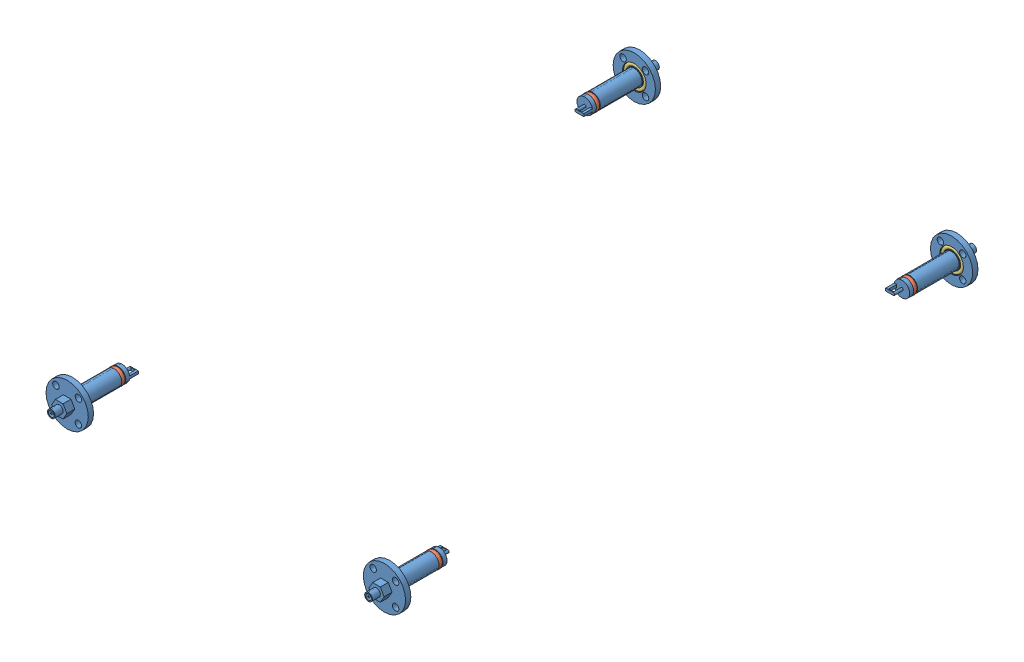
SolidWorks assembly sense_loop_quad_assy_a_1107, configuration Default. Lengths in mm.
Overall size (272 32 457).
32 component instances, 4 part files, 6 mates.
Components (placement in the parent):
- sense_loop_assy_a_1107-1: sense_loop_assy_a_1107 [Default] at (-120 0 -212.5) x (-1 0 0) z (0 0 1) size (32 32 60)
  - sense_loop_a_1107-1: sense_loop_a_1107 [Default] at origin size (32 32 60)
  - sense_loop_canted_1107-1: sense_loop_canted_1107 [Default] at (0 0 33) x (1 0 0) z (0 1 0) size (12 3 12)
  - sense_loop_oring_1107-1: sense_loop_oring_1107 [Default] at (0 0 -0.75) x (1 0 0) z (0 1 0) size (17.5 1.5 17.5)
  - Socket Head Cap Screw_AM-1: Socket Head Cap Screw_AM [B18.3.1M - 4 x 0.7 x 10 Hex SHCS -- 10NHX] at (-8.4853 -8.4853 -8) x (0 0 1) z (-0.030517 0.999534 0) size (14 7 7)
  - Socket Head Cap Screw_AM-2: Socket Head Cap Screw_AM [B18.3.1M - 4 x 0.7 x 10 Hex SHCS -- 10NHX] at (-8.4853 8.4853 -8) x (0 0 1) z (0.999534 0.030517 0) size (14 7 7)
  - Socket Head Cap Screw_AM-3: Socket Head Cap Screw_AM [B18.3.1M - 4 x 0.7 x 10 Hex SHCS -- 10NHX] at (8.4853 8.4853 -8) x (0 0 1) z (0.030517 -0.999534 0) size (14 7 7)
  - Socket Head Cap Screw_AM-4: Socket Head Cap Screw_AM [B18.3.1M - 4 x 0.7 x 10 Hex SHCS -- 10NHX] at (8.4853 -8.4853 -8) x (0 0 1) z (-0.999534 -0.030517 0) size (14 7 7)
- sense_loop_assy_a_1107-2: sense_loop_assy_a_1107 [Default] at (120 0 -212.5) size (32 32 60)
  - sense_loop_a_1107-1: sense_loop_a_1107 [Default] at origin size (32 32 60)
  - sense_loop_canted_1107-1: sense_loop_canted_1107 [Default] at (0 0 33) x (1 0 0) z (0 1 0) size (12 3 12)
  - sense_loop_oring_1107-1: sense_loop_oring_1107 [Default] at (0 0 -0.75) x (1 0 0) z (0 1 0) size (17.5 1.5 17.5)
  - Socket Head Cap Screw_AM-1: Socket Head Cap Screw_AM [B18.3.1M - 4 x 0.7 x 10 Hex SHCS -- 10NHX] at (-8.4853 -8.4853 -8) x (0 0 1) z (-0.030517 0.999534 0) size (14 7 7)
  - Socket Head Cap Screw_AM-2: Socket Head Cap Screw_AM [B18.3.1M - 4 x 0.7 x 10 Hex SHCS -- 10NHX] at (-8.4853 8.4853 -8) x (0 0 1) z (0.999534 0.030517 0) size (14 7 7)
  - Socket Head Cap Screw_AM-3: Socket Head Cap Screw_AM [B18.3.1M - 4 x 0.7 x 10 Hex SHCS -- 10NHX] at (8.4853 8.4853 -8) x (0 0 1) z (0.030517 -0.999534 0) size (14 7 7)
  - Socket Head Cap Screw_AM-4: Socket Head Cap Screw_AM [B18.3.1M - 4 x 0.7 x 10 Hex SHCS -- 10NHX] at (8.4853 -8.4853 -8) x (0 0 1) z (-0.999534 -0.030517 0) size (14 7 7)
- sense_loop_assy_a_1107-3: sense_loop_assy_a_1107 [Default] at (120 0 212.5) x (1 0 0) z (0 0 -1) size (32 32 60)
  - sense_loop_a_1107-1: sense_loop_a_1107 [Default] at origin size (32 32 60)
  - sense_loop_canted_1107-1: sense_loop_canted_1107 [Default] at (0 0 33) x (1 0 0) z (0 1 0) size (12 3 12)
  - sense_loop_oring_1107-1: sense_loop_oring_1107 [Default] at (0 0 -0.75) x (1 0 0) z (0 1 0) size (17.5 1.5 17.5)
  - Socket Head Cap Screw_AM-1: Socket Head Cap Screw_AM [B18.3.1M - 4 x 0.7 x 10 Hex SHCS -- 10NHX] at (-8.4853 -8.4853 -8) x (0 0 1) z (-0.030517 0.999534 0) size (14 7 7)
  - Socket Head Cap Screw_AM-2: Socket Head Cap Screw_AM [B18.3.1M - 4 x 0.7 x 10 Hex SHCS -- 10NHX] at (-8.4853 8.4853 -8) x (0 0 1) z (0.999534 0.030517 0) size (14 7 7)
  - Socket Head Cap Screw_AM-3: Socket Head Cap Screw_AM [B18.3.1M - 4 x 0.7 x 10 Hex SHCS -- 10NHX] at (8.4853 8.4853 -8) x (0 0 1) z (0.030517 -0.999534 0) size (14 7 7)
  - Socket Head Cap Screw_AM-4: Socket Head Cap Screw_AM [B18.3.1M - 4 x 0.7 x 10 Hex SHCS -- 10NHX] at (8.4853 -8.4853 -8) x (0 0 1) z (-0.999534 -0.030517 0) size (14 7 7)
- sense_loop_assy_a_1107-4: sense_loop_assy_a_1107 [Default] at (-120 0 212.5) x (-1 0 0) z (0 0 -1) size (32 32 60)
  - sense_loop_a_1107-1: sense_loop_a_1107 [Default] at origin size (32 32 60)
  - sense_loop_canted_1107-1: sense_loop_canted_1107 [Default] at (0 0 33) x (1 0 0) z (0 1 0) size (12 3 12)
  - sense_loop_oring_1107-1: sense_loop_oring_1107 [Default] at (0 0 -0.75) x (1 0 0) z (0 1 0) size (17.5 1.5 17.5)
  - Socket Head Cap Screw_AM-1: Socket Head Cap Screw_AM [B18.3.1M - 4 x 0.7 x 10 Hex SHCS -- 10NHX] at (-8.4853 -8.4853 -8) x (0 0 1) z (-0.030517 0.999534 0) size (14 7 7)
  - Socket Head Cap Screw_AM-2: Socket Head Cap Screw_AM [B18.3.1M - 4 x 0.7 x 10 Hex SHCS -- 10NHX] at (-8.4853 8.4853 -8) x (0 0 1) z (0.999534 0.030517 0) size (14 7 7)
  - Socket Head Cap Screw_AM-3: Socket Head Cap Screw_AM [B18.3.1M - 4 x 0.7 x 10 Hex SHCS -- 10NHX] at (8.4853 8.4853 -8) x (0 0 1) z (0.030517 -0.999534 0) size (14 7 7)
  - Socket Head Cap Screw_AM-4: Socket Head Cap Screw_AM [B18.3.1M - 4 x 0.7 x 10 Hex SHCS -- 10NHX] at (8.4853 -8.4853 -8) x (0 0 1) z (-0.999534 -0.030517 0) size (14 7 7)
Mates (geometry in assembly coordinates):
- Distance1: distance = 212.5 mm aligned: plane of assembly through (0 0 0) normal (0 0 1); plane of sense_loop_assy_a_1107-1/sense_loop_a_1107-1 through (-120 0 -212.5) normal (0 0 1)
- Coincident2: coincident anti-aligned: plane of sense_loop_assy_a_1107-1/sense_loop_a_1107-1; plane of assembly through (0 0 0) normal (0 1 0)
- Distance2: distance = 120 mm anti-aligned: plane of assembly through (0 0 0) normal (1 0 0); plane of sense_loop_assy_a_1107-1/sense_loop_a_1107-1
- Distance3: distance = 212.5 mm aligned: plane of sense_loop_assy_a_1107-2/sense_loop_a_1107-1 through (120 0 -212.5) normal (0 0 1); plane of assembly through (0 0 0) normal (0 0 1)
- Distance4: distance = 120 mm aligned: plane of sense_loop_assy_a_1107-2/sense_loop_a_1107-1 through (120 0 -212.5) normal (1 0 0); plane of assembly through (0 0 0) normal (1 0 0)
- Coincident6: coincident aligned: plane of sense_loop_assy_a_1107-2/sense_loop_a_1107-1 through (120 0 -212.5) normal (0 1 0); plane of assembly through (0 0 0) normal (0 1 0)
